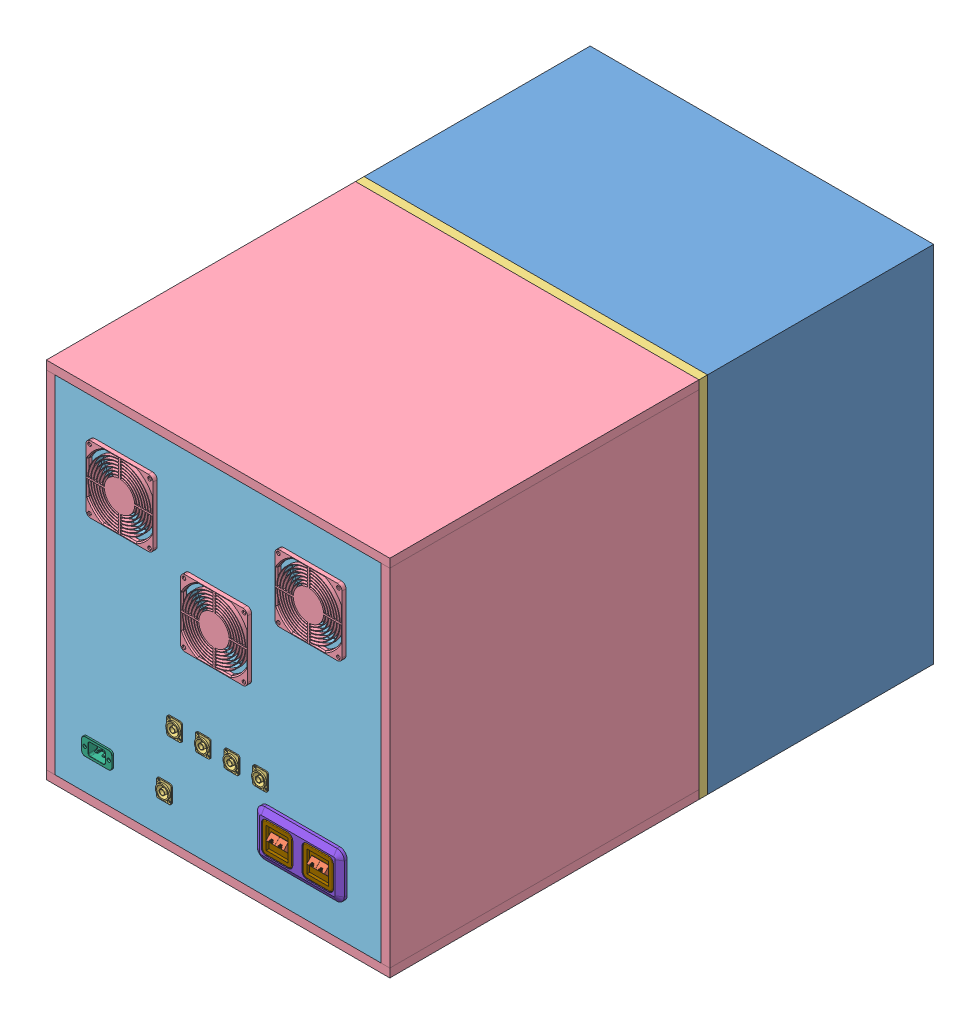
SolidWorks assembly Server, configuration Standard. Lengths in mm.
Overall size (600 687.5 965.02).
114 component instances, 39 part files, 37 mates.
Components (placement in the parent):
- Triton RBA-12-AD5-CAX-A1-1: Triton RBA-12-AD5-CAX-A1 [Standard] at (-276.3357 -337.3611 830.5) size (600 635 395)
- IPC 4U-4424-1: IPC 4U-4424 [Standard] at (240.1643 -104.0111 502.5) x (-1 0 0) z (0 0 -1) size (473 178 684)
- Verlängerung-1: Verlängerung [Standard] at (323.6643 -337.3611 832.5) size (600 635 570.02)
  - Lochplatte-1: Lochplatte [Standard] at (-600 0 0) size (600 635 15)
  - Platten-1: Platten [Standard] at (-600 620 555) x (1 0 0) z (0 1 0) size (600 540 15)
  - Platten-2: Platten [Standard] at (-600 0 555) x (1 0 0) z (0 1 0) size (600 540 15)
  - Platten-3: Platten [seite] at (-585 15 555) x (0 1 0) z (-1 0 0) size (605 540 15)
  - Platten-4: Platten [seite] at (0 15 555) x (0 1 0) z (-1 0 0) size (605 540 15)
  - Back-1: Back [Standard] at (-585 15 540) size (570 605 15)
  - 17322-1: 17322 [Default] at (-509 87 555) size (53 30 30)
  - Hohlwanddose-1: Hohlwanddose [Standard] at (-186 115 556) x (0 0 -1) z (1 0 0) size (60.7 71 71)
  - Hohlwanddose-2: Hohlwanddose [Standard] at (-115 115 556) x (0 0 -1) z (1 0 0) size (60.7 71 71)
  - Steckdose_2er-RJ45-1: Steckdose_2er-RJ45 [Standard] at (-243.8004 7.3351 555.8552) size (152 80 25.23)
    - Wandplatte-1: Wandplatte [2er] at (17.3004 67.6649 10.1448) size (152 80 11)
    - Steckdose-RJ45-1: Steckdose-RJ45 [Standard] at (177.7047 18.6812 -53.8826) x (0 -1 0) z (0 0 1) size (54 54 25.23)
      - Buchse-RJ45-1: Buchse-RJ45 [Standard] at (-88.9836 -48.9043 64.0274) size (54 54 6.5)
      - 65864-1: 65864 [Default] at (-88.8386 -41.2043 53.1274) size (17.49 15.42 25.23)
        - 65864_01-1: 65864_01 [Default] at origin size (9.69 0.75 13.83)
        - 65864_02-1: 65864_02 [Default] at origin size (9.44 0.68 13.83)
        - 65864_03-1: 65864_03 [Default] at origin size (9.69 0.61 13.84)
        - 65864_04-1: 65864_04 [Default] at origin size (9.44 0.54 13.83)
        - 65864_05-1: 65864_05 [Default] at origin size (9.69 0.54 13.82)
        - 65864_06-1: 65864_06 [Default] at origin size (9.44 0.6 13.83)
        - 65864_07-1: 65864_07 [Default] at origin size (9.69 0.68 13.83)
        - 65864_08-1: 65864_08 [Default] at origin size (9.44 0.75 13.83)
        - 65864_09-1: 65864_09 [Default] at origin size (17.11 15.1 23.65)
        - 65864_10-1: 65864_10 [Default] at origin size (6.36 10.31 6.36)
        - 65864_11-1: 65864_11 [Default] at origin size (17.49 15.42 25.23)
      - 65864-2: 65864 [Default] at (-88.8386 -56.6043 53.1274) size (17.49 15.42 25.23)
        - 65864_01-1: 65864_01 [Default] at origin size (9.69 0.75 13.83)
        - 65864_02-1: 65864_02 [Default] at origin size (9.44 0.68 13.83)
        - 65864_03-1: 65864_03 [Default] at origin size (9.69 0.61 13.84)
        - 65864_04-1: 65864_04 [Default] at origin size (9.44 0.54 13.83)
        - 65864_05-1: 65864_05 [Default] at origin size (9.69 0.54 13.82)
        - 65864_06-1: 65864_06 [Default] at origin size (9.44 0.6 13.83)
        - 65864_07-1: 65864_07 [Default] at origin size (9.69 0.68 13.83)
        - 65864_08-1: 65864_08 [Default] at origin size (9.44 0.75 13.83)
        - 65864_09-1: 65864_09 [Default] at origin size (17.11 15.1 23.65)
        - 65864_10-1: 65864_10 [Default] at origin size (6.36 10.31 6.36)
        - 65864_11-1: 65864_11 [Default] at origin size (17.49 15.42 25.23)
    - Steckdose-RJ45-2: Steckdose-RJ45 [Standard] at (106.7047 18.6812 -53.8826) x (0 -1 0) z (0 0 1) size (54 54 25.23)
      - Buchse-RJ45-1: Buchse-RJ45 [Standard] at (-88.9836 -48.9043 64.0274) size (54 54 6.5)
      - 65864-1: 65864 [Default] at (-88.8386 -41.2043 53.1274) size (17.49 15.42 25.23)
        - 65864_01-1: 65864_01 [Default] at origin size (9.69 0.75 13.83)
        - 65864_02-1: 65864_02 [Default] at origin size (9.44 0.68 13.83)
        - 65864_03-1: 65864_03 [Default] at origin size (9.69 0.61 13.84)
        - 65864_04-1: 65864_04 [Default] at origin size (9.44 0.54 13.83)
        - 65864_05-1: 65864_05 [Default] at origin size (9.69 0.54 13.82)
        - 65864_06-1: 65864_06 [Default] at origin size (9.44 0.6 13.83)
        - 65864_07-1: 65864_07 [Default] at origin size (9.69 0.68 13.83)
        - 65864_08-1: 65864_08 [Default] at origin size (9.44 0.75 13.83)
        - 65864_09-1: 65864_09 [Default] at origin size (17.11 15.1 23.65)
        - 65864_10-1: 65864_10 [Default] at origin size (6.36 10.31 6.36)
        - 65864_11-1: 65864_11 [Default] at origin size (17.49 15.42 25.23)
      - 65864-2: 65864 [Default] at (-88.8386 -56.6043 53.1274) size (17.49 15.42 25.23)
        - 65864_01-1: 65864_01 [Default] at origin size (9.69 0.75 13.83)
        - 65864_02-1: 65864_02 [Default] at origin size (9.44 0.68 13.83)
        - 65864_03-1: 65864_03 [Default] at origin size (9.69 0.61 13.84)
        - 65864_04-1: 65864_04 [Default] at origin size (9.44 0.54 13.83)
        - 65864_05-1: 65864_05 [Default] at origin size (9.69 0.54 13.82)
        - 65864_06-1: 65864_06 [Default] at origin size (9.44 0.6 13.83)
        - 65864_07-1: 65864_07 [Default] at origin size (9.69 0.68 13.83)
        - 65864_08-1: 65864_08 [Default] at origin size (9.44 0.75 13.83)
        - 65864_09-1: 65864_09 [Default] at origin size (17.11 15.1 23.65)
        - 65864_10-1: 65864_10 [Default] at origin size (6.36 10.31 6.36)
        - 65864_11-1: 65864_11 [Default] at origin size (17.49 15.42 25.23)
  - NBB75DFG-1: NBB75DFG [Standard] at (-393 87 555) x (-1 0 0) z (0 0 -1) size (26 31 34)
  - NBB75DFG-2: NBB75DFG [Standard] at (-375 190 555) x (-1 0 0) z (0 0 -1) size (26 31 34)
  - NBB75DFG-3: NBB75DFG [Standard] at (-325 190 555) x (-1 0 0) z (0 0 -1) size (26 31 34)
  - NBB75DFG-4: NBB75DFG [Standard] at (-275 190 555) x (-1 0 0) z (0 0 -1) size (26 31 34)
  - NBB75DFG-5: NBB75DFG [Standard] at (-225 190 555) x (-1 0 0) z (0 0 -1) size (26 31 34)
  - Schutz-2: Schutz [Standard] at (-135 500 555) size (117 117 7.2)
  - Schutz-3: Schutz [Standard] at (-300 380 555) size (117 117 7.2)
  - 46362-1: 46362 [Default] at (-135 500 540) x (-1 0 0) z (0 0 -1) size (119.05 119.01 25.4)
  - 46362-2: 46362 [Default] at (-465 500 540) x (-1 0 0) z (0 0 -1) size (119.05 119.01 25.4)
  - 46362-3: 46362 [Default] at (-300 380 540) x (-1 0 0) z (0 0 -1) size (119.05 119.01 25.4)
  - Schutz-1: Schutz [Standard] at (-465 500 555) size (117 117 7.2)
- caster_2001_5-02-1: caster_2001_5-02 [Default] at (-203.8357 -370.8611 510) size (41 52.5 45)
  - caster_2001_5-02_01-1: caster_2001_5-02_01 [Default] at origin size (22 38 38)
  - caster_2001_5-02_02-1: caster_2001_5-02_02 [Default] at origin size (41 38.4 45)
- caster_2001_5-02-2: caster_2001_5-02 [Default] at (251.1643 -370.8611 1315) size (41 52.5 45)
  - caster_2001_5-02_01-1: caster_2001_5-02_01 [Default] at origin size (22 38 38)
  - caster_2001_5-02_02-1: caster_2001_5-02_02 [Default] at origin size (41 38.4 45)
- caster_2001_5-02-3: caster_2001_5-02 [Default] at (251.1643 -370.8611 510) size (41 52.5 45)
  - caster_2001_5-02_01-1: caster_2001_5-02_01 [Default] at origin size (22 38 38)
  - caster_2001_5-02_02-1: caster_2001_5-02_02 [Default] at origin size (41 38.4 45)
- caster_2001_5-02-4: caster_2001_5-02 [Default] at (-203.8357 -370.8611 1315) size (41 52.5 45)
  - caster_2001_5-02_01-1: caster_2001_5-02_01 [Default] at origin size (22 38 38)
  - caster_2001_5-02_02-1: caster_2001_5-02_02 [Default] at origin size (41 38.4 45)
- USV-1: USV [Standard] at (240.1643 -192.8611 502.5) x (-1 0 0) z (0 0 -1) size (473 89 509)
- 3com-eth-sfp-switch-1: 3com-eth-sfp-switch [Default] at (23.868 -236.86 587.209) x (-1 -0.000472 0) z (0 0 -1) size (470.41 43.94 178.3)
- 3com-eth-sfp-switch-2: 3com-eth-sfp-switch [Default] at (23.868 -281.31 587.209) x (-1 -0.000472 0) z (0 0 -1) size (470.41 43.94 178.3)
- IPC 2U-2129N-1: IPC 2U-2129N [Standard] at (240.1643 73.8389 502.5) x (-1 0 0) z (0 0 -1) size (473 89 714)
- Router-Schublade-1: Router-Schublade [Standard] at (18.9831 120.7346 1400.9) x (-1 0 0) z (0 0 -1) size (464.8 84.05 758)
  - Platte-1: Platte [Standard] at (-201.5811 50.5043 900) size (393.8 15 700)
  - Gleitschiene-Left-1: Gleitschiene-Left [Standard] at (-230.5216 -87.7457 847.2457) x (0 0 1) z (0 1 0) size (537 44.1 44)
    - winkel-1: winkel [Standard] at (51.9543 -6.5595 130.1) size (152.1 17.5 44)
    - Schine-1: Schine [Standard] at (-484.2457 10.9405 134.15) x (0 1 0) z (1 0 0) size (13.6 35 510)
    - Rolle-1: Rolle [Standard] at (-471.2457 35.9405 133.25) x (0 1 0) z (1 0 0) size (19.2 41.6 507)
  - Gleitschiene-Right-1: Gleitschiene-Right [Standard] at (221.1594 215.5543 847.2457) x (0 0 1) z (0 -1 0) size (537 44.1 44.05)
    - winkel-1: winkel [Standard] at (51.9543 -6.5595 130.1) size (152.1 17.5 44)
    - Schine-1: Schine [Standard] at (-484.2457 10.9405 134.15) x (0 1 0) z (1 0 0) size (13.6 35 510)
    - Rolle-1: Rolle [Standard] at (15.7543 35.9405 170.05) x (0 1 0) z (-1 0 0) size (19.2 41.6 507)
  - Modem-1: Modem [Standard] at (168.2189 115.5043 580) x (-1 0 0) z (0 -1 0) size (205 180 50)
  - Router-1: Router [Standard] at (168.2189 65.5043 900) x (0 0 -1) z (1 0 0) size (260 40 200)
  - Keystone Housing-1: Keystone Housing [Standard] at (-29.8854 65.5043 360) x (0 0 -1) z (1 0 0) size (218 30.5 94)
  - Keystone Housing-2: Keystone Housing [Standard] at (10.1146 65.5043 142) x (0 0 1) z (-1 0 0) size (218 30.5 94)
  - Kanal-1: Kanal [500] at (-56.7811 65.5043 400) size (40 60 500)
  - Kanal-2: Kanal [160] at (-9.8854 65.5043 200) size (40 60 160)
  - Seite-1: Seite [Standard] at (-201.5811 65.5043 142) size (24 48 758)
  - Seite-2: Seite [Standard] at (168.2189 65.5043 142) size (24 48 758)
  - Steckdose-1: Steckdose [Standard] at (-177.5811 65.5043 740) size (53 40 340)
  - Kanal-3: Kanal [345,8] at (168.2189 65.5043 380) x (0 0 1) z (-1 0 0) size (40 60 345.8)
  - Raspberry Pi 4 B-1: Raspberry Pi 4 B [默认] at (-135.4811 65.5043 851.3868) x (0 0 -1) z (0 1 0) size (86.92 58.6 19)
Mates (geometry in assembly coordinates):
- Deckungsgleich5: coincident anti-aligned: plane of Triton RBA-12-AD5-CAX-A1-1 through (-276.3357 -337.3611 832.5) normal (0 0 1); plane of Verlängerung-1/Lochplatte-1 through (-276.3357 -337.3611 832.5) normal (0 0 -1)
- Deckungsgleich6: coincident anti-aligned: circle of Triton RBA-12-AD5-CAX-A1-1; cylinder of Verlängerung-1/Lochplatte-1 through (-185.3357 276.6389 847.5) axis (0 0 -1) radius 6
- Konzentrisch1: concentric anti-aligned: cylinder of Triton RBA-12-AD5-CAX-A1-1 through (232.6643 -316.3611 830.5) axis (0 0 1) radius 6; cylinder of Verlängerung-1/Lochplatte-1 through (232.6643 -316.3611 847.5) axis (0 0 -1) radius 6
- Deckungsgleich7: coincident anti-aligned: plane of Verlängerung-1/Platten-2 through (-276.3357 -337.3611 1387.5) normal (0 -1 0); plane of caster_2001_5-02-1/caster_2001_5-02_02-1 through (-218.3357 -337.3611 517.5147) normal (0 1 0)
- Deckungsgleich8: coincident anti-aligned: plane of Verlängerung-1/Platten-2 through (-276.3357 -337.3611 1387.5) normal (0 -1 0); plane of caster_2001_5-02-2/caster_2001_5-02_02-1 through (236.6643 -337.3611 1322.5147) normal (0 1 0)
- Deckungsgleich9: coincident anti-aligned: plane of Triton RBA-12-AD5-CAX-A1-1 through (-276.3357 -337.3611 832.5) normal (0 -1 0); plane of caster_2001_5-02-3/caster_2001_5-02_02-1 through (236.6643 -337.3611 517.5147) normal (0 1 0)
- Deckungsgleich10: coincident anti-aligned: plane of Triton RBA-12-AD5-CAX-A1-1 through (-276.3357 -337.3611 832.5) normal (0 -1 0); plane of caster_2001_5-02-4/caster_2001_5-02_02-1 through (-218.3357 -337.3611 1322.5147) normal (0 1 0)
- Deckungsgleich11: coincident aligned: plane of caster_2001_5-02-1/caster_2001_5-02_02-1 through (-216.3357 -337.3611 517.5147) normal (-1 0 0); plane of caster_2001_5-02-4/caster_2001_5-02_02-1 through (-216.3357 -337.3611 1322.5147) normal (-1 0 0)
- Deckungsgleich12: coincident aligned: plane of caster_2001_5-02-2/caster_2001_5-02_02-1 through (237.1643 -337.3611 1337.5) normal (0 0 1); plane of caster_2001_5-02-4/caster_2001_5-02_02-1 through (-217.8357 -337.3611 1337.5) normal (0 0 1)
- Deckungsgleich13: coincident aligned: plane of caster_2001_5-02-2/caster_2001_5-02_02-1 through (263.6643 -337.3611 1322.5147) normal (1 0 0); plane of caster_2001_5-02-3/caster_2001_5-02_02-1 through (263.6643 -337.3611 517.5147) normal (1 0 0)
- Deckungsgleich14: coincident aligned: plane of caster_2001_5-02-1/caster_2001_5-02_02-1 through (-217.8357 -337.3611 487.5) normal (0 0 -1); plane of caster_2001_5-02-3/caster_2001_5-02_02-1 through (237.1643 -337.3611 487.5) normal (0 0 -1)
- Abstand2: distance = 50 mm aligned: plane of caster_2001_5-02-1/caster_2001_5-02_02-1 through (-217.8357 -337.3611 487.5) normal (0 0 -1); plane of Triton RBA-12-AD5-CAX-A1-1 through (-276.3357 -337.3611 437.5) normal (0 0 -1)
- Abstand3: distance = 60 mm aligned: plane of caster_2001_5-02-1/caster_2001_5-02_02-1 through (-216.3357 -337.3611 517.5147) normal (-1 0 0); plane of Triton RBA-12-AD5-CAX-A1-1 through (-276.3357 -337.3611 832.5) normal (-1 0 0)
- Abstand4: distance = 60 mm aligned: plane of caster_2001_5-02-3/caster_2001_5-02_02-1 through (263.6643 -337.3611 517.5147) normal (1 0 0); plane of Triton RBA-12-AD5-CAX-A1-1 through (323.6643 -337.3611 832.5) normal (1 0 0)
- Abstand5: distance = 50 mm aligned: plane of caster_2001_5-02-2/caster_2001_5-02_02-1 through (237.1643 -337.3611 1337.5) normal (0 0 1); plane of Verlängerung-1/Platten-2 through (-276.3357 -322.3611 1387.5) normal (0 0 1)
- Deckungsgleich19: coincident anti-aligned: plane of Triton RBA-12-AD5-CAX-A1-1 through (-192.8357 275.6389 506.5) normal (1 0 0); plane of IPC 4U-4424-1 through (-192.8357 73.9889 502.5) normal (-1 0 0)
- Deckungsgleich20: coincident anti-aligned: plane of Triton RBA-12-AD5-CAX-A1-1 through (-276.3357 -337.3611 502.5) normal (0 0 -1); plane of IPC 4U-4424-1 through (240.1643 -104.0111 502.5) normal (0 0 1)
- Konzentrisch2: concentric anti-aligned: cylinder of Triton RBA-12-AD5-CAX-A1-1 through (-202.8357 -97.5611 496.5) axis (0 0 1) radius 2.5; cylinder of IPC 4U-4424-1 through (-202.8357 -97.5611 508.5) axis (0 0 -1) radius 2.5
- Deckungsgleich21: coincident anti-aligned: plane of Triton RBA-12-AD5-CAX-A1-1 through (-276.3357 -337.3611 502.5) normal (0 0 -1); plane of USV-1 through (240.1643 -192.8611 502.5) normal (0 0 1)
- Deckungsgleich22: coincident anti-aligned: plane of Triton RBA-12-AD5-CAX-A1-1 through (240.1643 275.6389 506.5) normal (-1 0 0); plane of USV-1 through (240.1643 -103.8611 502.5) normal (1 0 0)
- Konzentrisch3: concentric anti-aligned: cylinder of Triton RBA-12-AD5-CAX-A1-1 through (250.1643 -186.4611 496.5) axis (0 0 1) radius 2.5; cylinder of USV-1 through (250.1643 -186.4611 508.5) axis (0 0 -1) radius 2.5
- Deckungsgleich23: coincident anti-aligned: plane of Triton RBA-12-AD5-CAX-A1-1 through (-276.3357 -337.3611 502.5) normal (0 0 -1); plane of 3com-eth-sfp-switch-1 through (259.0513 -192.8069 502.5) normal (0 0 1)
- Konzentrisch4: concentric anti-aligned: cylinder of Triton RBA-12-AD5-CAX-A1-1 through (250.1643 -199.1611 496.5) axis (0 0 1) radius 2.5; cylinder of 3com-eth-sfp-switch-1 through (250.1643 -199.1611 512.7233) axis (0 0 -1) radius 2.286
- Tangential1: tangent anti-aligned: cylinder of Triton RBA-12-AD5-CAX-A1-1 through (-202.8357 -199.1611 496.5) axis (0 0 1) radius 2.5; plane of 3com-eth-sfp-switch-1 through (-202.4626 -201.6609 512.7233) normal (-0.000472 1 0)
- Deckungsgleich26: coincident anti-aligned: plane of Triton RBA-12-AD5-CAX-A1-1 through (-276.3357 -337.3611 502.5) normal (0 0 -1); plane of 3com-eth-sfp-switch-2 through (259.0513 -237.2569 502.5) normal (0 0 1)
- Konzentrisch6: concentric anti-aligned: cylinder of Triton RBA-12-AD5-CAX-A1-1 through (250.1643 -243.6111 496.5) axis (0 0 1) radius 2.5; cylinder of 3com-eth-sfp-switch-2 through (250.1643 -243.6111 512.7233) axis (0 0 -1) radius 2.286
- Tangential2: tangent anti-aligned: cylinder of Triton RBA-12-AD5-CAX-A1-1 through (-202.8357 -243.6111 496.5) axis (0 0 1) radius 2.5; plane of 3com-eth-sfp-switch-2 through (-202.4626 -246.1109 512.7233) normal (-0.000472 1 0)
- Deckungsgleich27: coincident anti-aligned: plane of Triton RBA-12-AD5-CAX-A1-1 through (240.1643 275.6389 506.5) normal (-1 0 0); plane of IPC 2U-2129N-1 through (240.1643 162.8389 502.5) normal (1 0 0)
- Deckungsgleich28: coincident anti-aligned: plane of Triton RBA-12-AD5-CAX-A1-1 through (-276.3357 -337.3611 502.5) normal (0 0 -1); plane of IPC 2U-2129N-1 through (240.1643 73.8389 502.5) normal (0 0 1)
- Konzentrisch7: concentric anti-aligned: cylinder of Triton RBA-12-AD5-CAX-A1-1 through (250.1643 80.2389 496.5) axis (0 0 1) radius 2.5; cylinder of IPC 2U-2129N-1 through (250.1643 80.2389 508.5) axis (0 0 -1) radius 2.5
- Deckungsgleich29: coincident: plane of Triton RBA-12-AD5-CAX-A1-1 through (240.1643 275.6389 506.5) normal (-1 0 0); plane of ? through (240.1643 207.1061 503) normal (1 0 0)
- Deckungsgleich30: coincident anti-aligned: plane of Triton RBA-12-AD5-CAX-A1-1 through (-276.3357 -337.3611 502.5) normal (0 0 -1); plane of ? through (255.2643 207.1061 502.5) normal (0 0 1)
- Deckungsgleich31: coincident anti-aligned: plane of Triton RBA-12-AD5-CAX-A1-1 through (-192.8357 275.6389 506.5) normal (1 0 0); plane of ? through (-192.8357 163.3327 503) normal (-1 0 0)
- Deckungsgleich32: coincident anti-aligned: plane of Triton RBA-12-AD5-CAX-A1-1 through (-276.3357 -337.3611 502.5) normal (0 0 -1); plane of ? through (-207.9357 163.3327 502.5) normal (0 0 1)
- Deckungsgleich33: coincident anti-aligned: plane of Triton RBA-12-AD5-CAX-A1-1 through (-276.3357 -337.3611 502.5) normal (0 0 -1); plane of Router-Schublade-1/Gleitschiene-Left-1/winkel-1 through (255.2643 207.0889 502.5) normal (0 0 1)
- Deckungsgleich34: coincident anti-aligned: plane of Triton RBA-12-AD5-CAX-A1-1 through (240.1643 275.6389 506.5) normal (-1 0 0); plane of Router-Schublade-1/Gleitschiene-Left-1/winkel-1 through (240.1643 207.0889 503) normal (1 0 0)
- Langloch1: slot anti-aligned: cylinder of Router-Schublade-1/Gleitschiene-Left-1/winkel-1 through (250.9143 169.1389 544.9) axis (0 0 -1) radius 3.05; cylinder of Triton RBA-12-AD5-CAX-A1-1 through (250.1643 169.1389 496.5) axis (0 0 1) radius 2.5; cylinder of Router-Schublade-1/Gleitschiene-Left-1/winkel-1 through (247.0143 169.1389 544.9) axis (0 0 -1) radius 3.05
